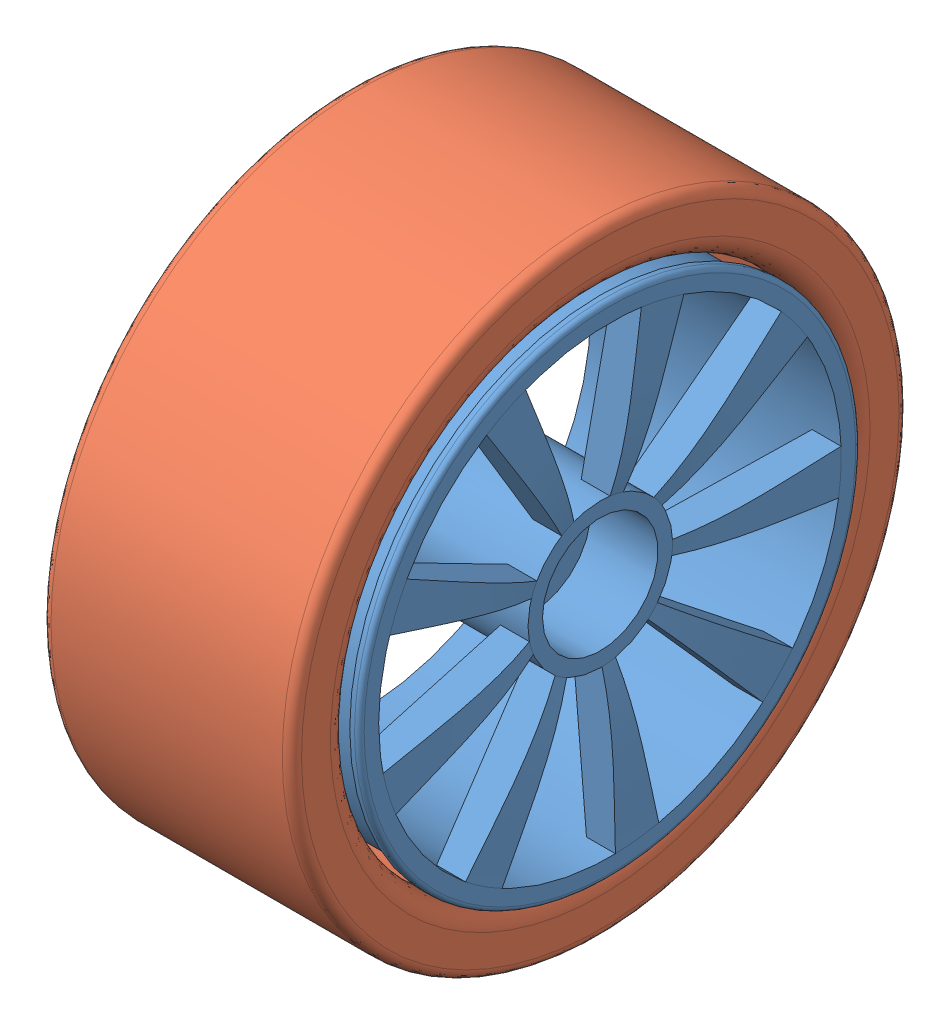
SolidWorks assembly Assem1, configuration Default. Lengths in mm.
Overall size (27.11 64 64).
2 component instances, 2 part files, 2 mates.
Components (placement in the parent):
- Rim-1: Rim [Default] at (-11.8873 36.5214 50.0537) size (26.11 52 52)
- Tire-1: Tire [Default] at (-25.8873 36.5214 50.0537) size (26 64 64)
Mates (geometry in assembly coordinates):
- Concentric1: concentric aligned: cylinder of Rim-1 through (-101.4428 36.5214 50.0537) axis (-1 0 0) radius 25; cylinder of Tire-1 through (0.1127 36.5214 50.0537) axis (-1 0 0) radius 30
- Tangent2: tangent: plane of Rim-1 through (0.1127 36.5214 24.0537) normal (-1 0 0); torus of Tire-1
